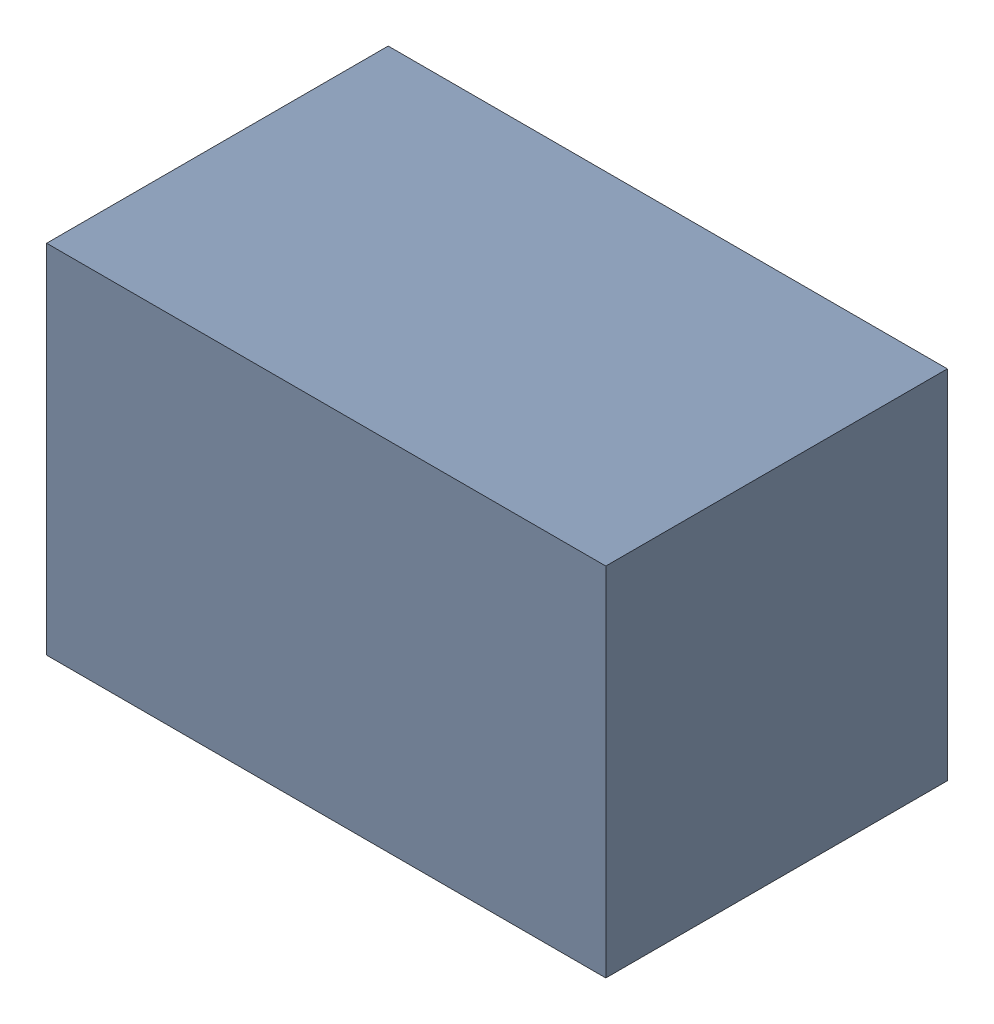
SolidWorks assembly C41, configuration Default. Lengths in mm.
Overall size (2.21 1.41 1.35).
3 component instances, 2 part files, 0 mates.
Components (placement in the parent):
- 1088885792-1: 1088885792 [Default] at (13.2 17.1 -2.994) size (2.21 1.41 1.35)
  - Extruded-46-1: Extruded-46 [Default] at origin size (2.21 1.41 1.35)
- C0805_2012D-1: C0805_2012D [Default] at (14.2001 16.4749 -1.644) x (-1 0 0) z (0 -1 0) size (2 1.25 1.25)
